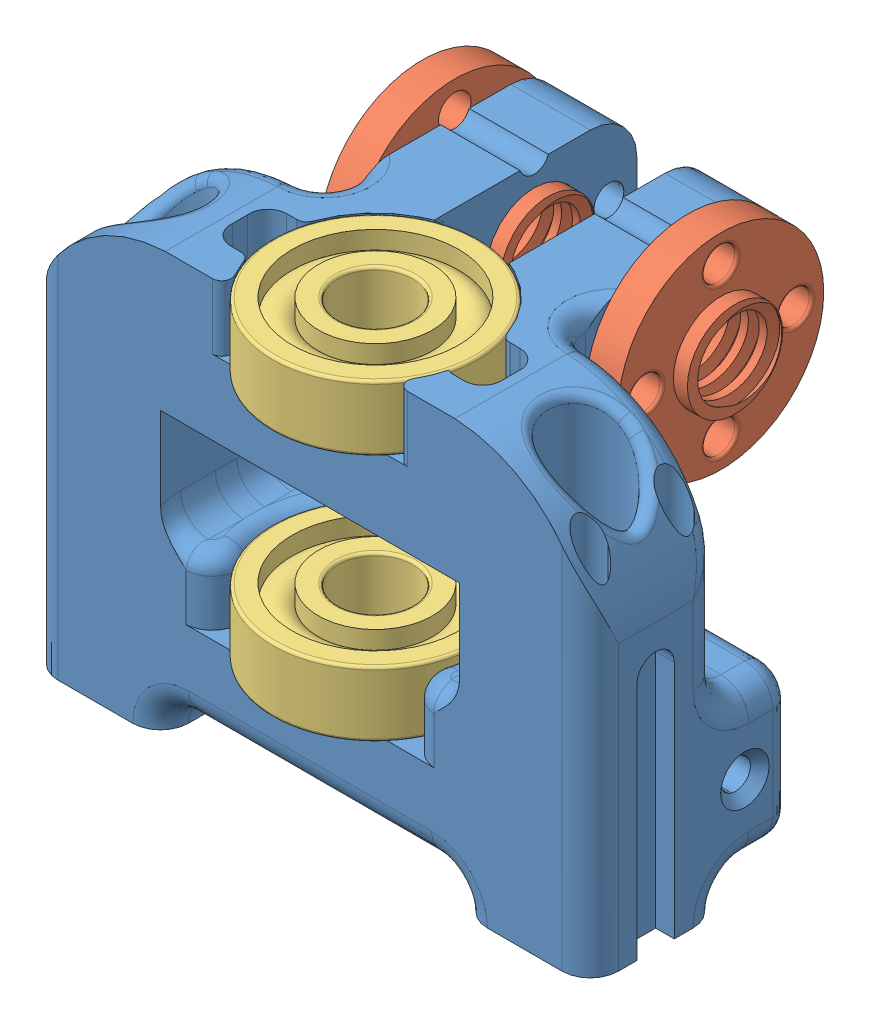
SolidWorks assembly x lead idler block, configuration Default. Lengths in mm.
Overall size (60 49 43).
6 component instances, 4 part files, 8 mates.
Components (placement in the parent):
- x idler lead mirror-1: x idler lead mirror [Default] at (2.4627 -2.0246 79.4222) size (60 45.79 39.16)
- LeadScrew Nut 8mm x 2mmPitch (1)-1: LeadScrew Nut 8mm x 2mmPitch (1) [Default] at (-13.5373 17.9754 51.4222) x (0 0 1) z (-1 0 0) size (22 22 16.05)
- LeadScrew Nut 8mm x 2mmPitch (1)-2: LeadScrew Nut 8mm x 2mmPitch (1) [Default] at (18.4627 17.9754 51.4222) x (0 0 -1) z (1 0 0) size (22 22 16.05)
- instrument ball bearing_68_iso-1: instrument ball bearing_68_iso [ISO 1224 - 100822 - R,8,SI,NC,8_68] at (2.4627 -4.5246 72.4222) x (0 -1 0) z (0 0 1) size (7 22 22)
- instrument ball bearing_68_iso-2: instrument ball bearing_68_iso [ISO 1224 - 100822 - R,8,SI,NC,8_68] at (2.4627 21.9754 72.4222) x (0 1 0) z (0 0 1) size (7 22 22)
- brass sleeve 30mm-1: brass sleeve 30mm [Default] at (2.4627 -9.0246 51.4222) x (0 0 1) z (-1 0 0) size (11 11 30)
Mates (geometry in assembly coordinates):
- Coincidente1: coincident anti-aligned: plane of x idler lead mirror-1 through (-10.0373 17.9754 51.4222) normal (-1 0 0); plane of LeadScrew Nut 8mm x 2mmPitch (1)-1 through (-10.0373 17.9754 51.4222) normal (1 0 0)
- Concentrico1: concentric aligned: cylinder of x idler lead mirror-1 through (32.4637 17.9754 51.4222) axis (-1 0 0) radius 5.15; cylinder of LeadScrew Nut 8mm x 2mmPitch (1)-1 through (-10.0373 17.9754 51.4222) axis (-1 0 0) radius 11
- Concentrico2: concentric aligned: cylinder of x idler lead mirror-1 through (2.4627 -8.0246 72.4222) axis (0 1 0) radius 11.05; cylinder of instrument ball bearing_68_iso-2 through (2.4627 1.3379 72.4222) axis (0 1 0) radius 4
- Concentrico3: concentric anti-aligned: cylinder of x idler lead mirror-1 through (2.4627 18.4754 72.4222) axis (0 1 0) radius 11.05; cylinder of instrument ball bearing_68_iso-1 through (2.4627 16.1129 72.4222) axis (0 -1 0) radius 11
- Coincidente2: coincident aligned: plane of x idler lead mirror-1 through (-13.5373 25.4754 114.7634) normal (0 1 0); plane of instrument ball bearing_68_iso-2 through (-8.2373 25.4754 72.4222) normal (0 1 0)
- Coincidente3: coincident anti-aligned: plane of x idler lead mirror-1 through (2.4627 -8.0246 72.4222) normal (0 1 0); plane of instrument ball bearing_68_iso-1 through (13.1627 -8.0246 72.4222) normal (0 -1 0)
- Concentrico4: concentric anti-aligned: cylinder of x idler lead mirror-1 through (2.4627 -9.0246 51.4222) axis (-1 0 0) radius 5.6; cylinder of brass sleeve 30mm-1 through (-27.5373 -9.0246 51.4222) axis (1 0 0) radius 5.5
- Coincidente4: coincident aligned: plane of x idler lead mirror-1 through (-27.5373 47.9754 65.4222) normal (-1 0 0); plane of brass sleeve 30mm-1 through (-27.5373 -9.0246 51.4222) normal (-1 0 0)
